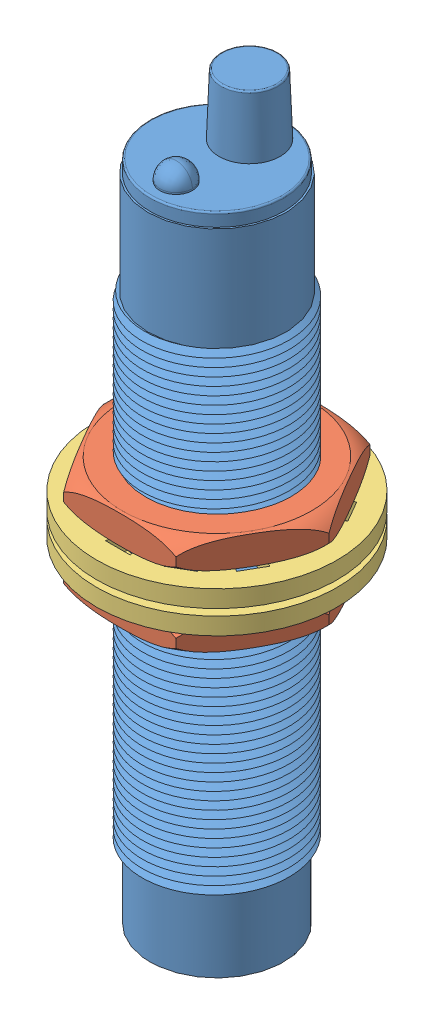
SolidWorks assembly LJ18A3-8-ZBX, configuration Default. Lengths in mm.
Overall size (29.9 88.8 29.5).
5 component instances, 3 part files, 0 mates.
Components (placement in the parent):
- LJ18A3-8-ZBX_BODY-1: LJ18A3-8-ZBX_BODY [Default] at origin size (18.52 88.8 18.52)
- LJ18A3-8-ZBX_NUT-1: LJ18A3-8-ZBX_NUT [Default] at (0 28.3 0) size (29.9 5.82 27.52)
- LJ18A3-8-ZBX_NUT-2: LJ18A3-8-ZBX_NUT [Default] at (0 36.95 0) size (29.9 5.82 27.52)
- LJ18A3-8-ZBX_WASHER-1: LJ18A3-8-ZBX_WASHER [Default] at (0 34.85 0) size (29.5 2.1 29.5)
- LJ18A3-8-ZBX_WASHER-2: LJ18A3-8-ZBX_WASHER [Default] at (0 31.95 0) size (29.5 2.1 29.5)
